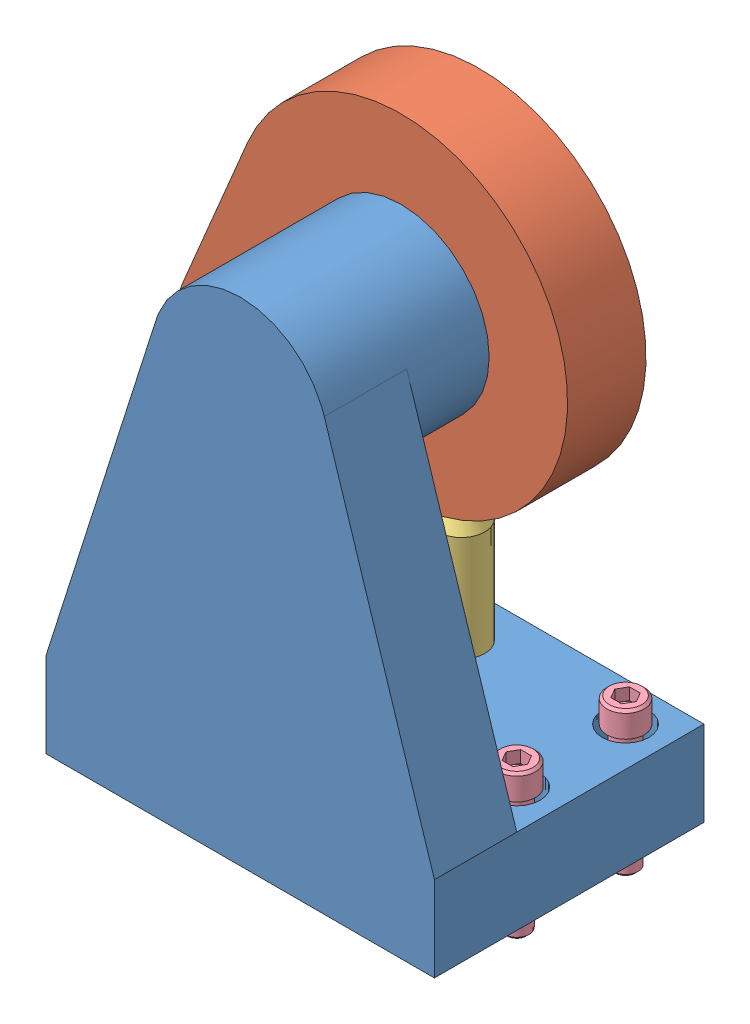
SolidWorks assembly Assem8, configuration Predeterminado. Lengths in mm.
Overall size (139.01 202.38 68.74).
7 component instances, 4 part files, 0 mates.
Components (placement in the parent):
- Part12-1: Part12 [Predeterminado] at origin size (99.06 125.65 68.74)
- Part11-1: Part11 [Predeterminado] at (0 0 -20) x (-0.604132 0.796885 0) z (0 0 1) size (85 110 40)
- Part13-1: Part13 [Predeterminado] at (0 -107.2897 -15.4065) x (0.949466 0 -0.313868) z (0.313868 0 0.949466) size (12 100 12)
- Socket Head Cap Screw_AI_HX-SHCS 0.25-20x1.25x1.25-N-1: Socket Head Cap Screw_AI_HX-SHCS 0.25-20x1.25x1.25-N [Predeterminado] at (39.5293 -75.0813 -17.744) x (0 -1 0) z (0 0 1) size (38.1 9.53 9.53)
- Socket Head Cap Screw_AI_HX-SHCS 0.25-20x1.25x1.25-N-2: Socket Head Cap Screw_AI_HX-SHCS 0.25-20x1.25x1.25-N [Predeterminado] at (-39.5293 -75.0813 -17.744) x (0 -1 0) z (0 0 1) size (38.1 9.53 9.53)
- Socket Head Cap Screw_AI_HX-SHCS 0.25-20x1.25x1.25-N-3: Socket Head Cap Screw_AI_HX-SHCS 0.25-20x1.25x1.25-N [Predeterminado] at (-39.5293 -75.0813 10) x (0 -1 0) z (0 0 1) size (38.1 9.53 9.53)
- Socket Head Cap Screw_AI_HX-SHCS 0.25-20x1.25x1.25-N-4: Socket Head Cap Screw_AI_HX-SHCS 0.25-20x1.25x1.25-N [Predeterminado] at (39.5293 -75.0813 10) x (0 -1 0) z (0 0 1) size (38.1 9.53 9.53)
